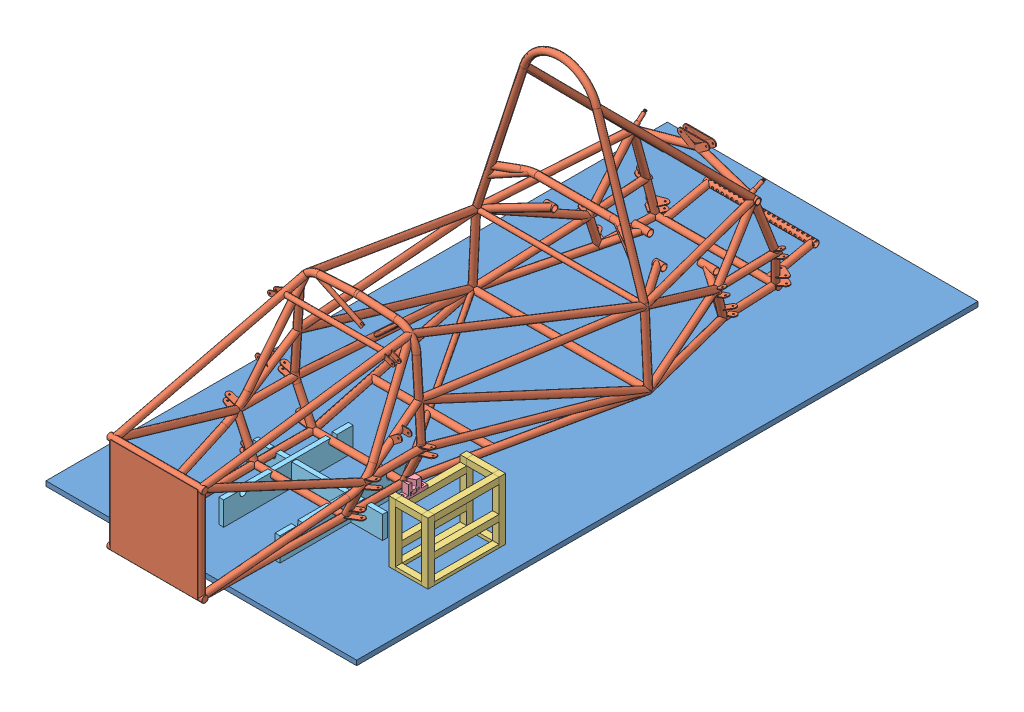
SolidWorks assembly jig assy (2023-11-19), configuration Default. Lengths in mm.
Overall size (1219.2 1075.77 2624.79).
7 component instances, 5 part files, 14 mates.
Components (placement in the parent):
- base board-1: base board [Default] at origin size (1219.2 19.05 2438.4)
- 22_Frame_Final-Chassis_V1-1: 22_Frame_Final-Chassis_V1 [Default Chassis<As Machined>] at (0 294.9364 603.8357) x (0 0 1) z (0 -1 0) size (2395.6 1129.53 988.36)
- front jig cage-1: front jig cage [Default] at (431.8 6.35 685.8) x (0 0 -1) z (1 0 0) size (304.8 254 152.4)
- FLUF block-1: FLUF block [Default] at (355.6 234.95 762) x (0 0 -1) z (1 0 0) size (101.6 50.8 84.95)
- front riser 1-1: front riser 1 [Default] at (-254 6.35 742.95) size (508 101.6 19.05)
- front riser 1-2: front riser 1 [Default] at (-121.7808 10.5883 1028.5888) x (0 0 -1) z (1 0 0) size (508 101.6 19.05)
- front riser 1-5: front riser 1 [Default] at (110.3205 10.5883 1040.0261) x (0 0 -1) z (1 0 0) size (508 101.6 19.05)
Mates (geometry in assembly coordinates):
- Coincident1: coincident aligned: plane of base board-1 through (0 0 0) normal (0 0 1)
- Coincident2: coincident aligned: plane of base board-1 through (0 0 0) normal (0 1 0)
- Coincident3: coincident aligned: plane of base board-1 through (0 0 0) normal (1 0 0)
- Coincident4: coincident anti-aligned: plane of 22_Frame_Final-Chassis_V1-1 through (0 294.9364 603.8357) normal (-1 0 0)
- Coincident5: coincident anti-aligned: plane of base board-1 through (0 6.35 0) normal (0 1 0); plane of front jig cage-1 through (431.8 6.35 685.8) normal (0 -1 0)
- Coincident6: coincident anti-aligned: plane of base board-1 through (355.6 6.35 838.2) normal (1 0 0); plane of front jig cage-1 through (355.6 260.35 685.8) normal (-1 0 0)
- Coincident7: coincident anti-aligned: plane of base board-1 through (508 6.35 838.2) normal (0 0 -1); plane of front jig cage-1 through (431.8 260.35 838.2) normal (0 0 1)
- Coincident8: coincident anti-aligned: plane of front jig cage-1 through (381 234.95 838.202) normal (0 1 0); plane of FLUF block-1 through (381 234.95 812.8) normal (0 -1 0)
- Coincident9: coincident aligned: plane of front jig cage-1 through (381 234.95 838.202) normal (1 0 0); plane of FLUF block-1 through (381 234.95 762) normal (1 0 0)
- Distance3: distance = 25.4 mm aligned: plane of FLUF block-1 through (381 247.65 812.8) normal (0 0 1); plane of front jig cage-1 through (431.8 260.35 838.2) normal (0 0 1)
- Coincident10: coincident anti-aligned: plane of base board-1 through (-254 6.35 742.95) normal (0 0 1); plane of front riser 1-1 through (-254 6.35 742.95) normal (0 0 -1)
- Coincident11: coincident anti-aligned: plane of base board-1 through (254 6.35 742.95) normal (-1 0 0); plane of front riser 1-1 through (254 6.35 762) normal (1 0 0)
- Coincident12: coincident anti-aligned: plane of base board-1 through (0 6.35 0) normal (0 1 0); plane of front riser 1-1 through (-254 6.35 762) normal (0 -1 0)
- Coincident15: coincident aligned: plane of front riser 1-2 through (-102.7308 112.1883 1028.5888) normal (0 1 0); plane of front riser 1-5 through (129.3705 112.1883 1040.0261) normal (0 1 0)
